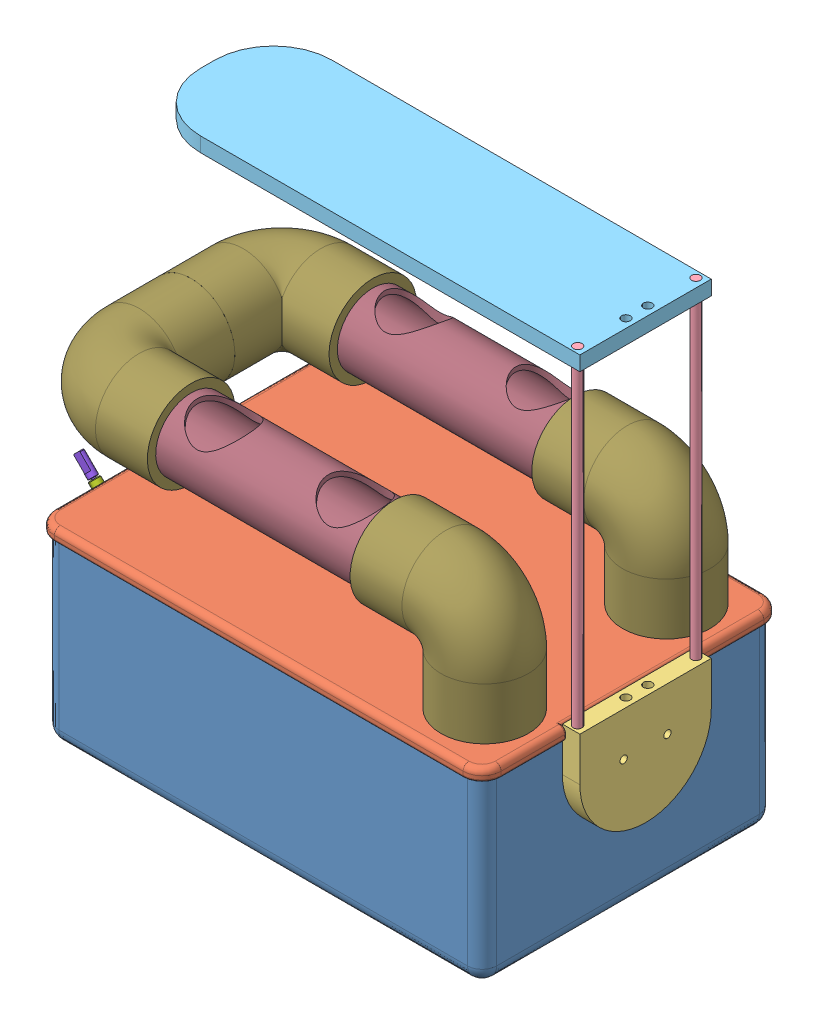
SolidWorks assembly Prototype1, configuration Default. Lengths in mm.
Overall size (357.64 356 206).
22 component instances, 13 part files, 37 mates.
Components (placement in the parent):
- Casing-1: Casing [Default] at (112.1733 69.847 255.1145) size (300 127 200)
- Tapa-1: Tapa [Default] at (112.1733 196.847 255.1145) size (306 8 206)
- BarsHolder-1: BarsHolder [Default] at (262.1733 170.847 255.1145) size (12 75 90)
- 15cmAluminumBar-1: 15cmAluminumBar [Default] at (268.1733 175.847 295.6145) size (6 250 6)
- 15cmAluminumBar-6: 15cmAluminumBar [Default] at (268.1733 175.847 214.6145) x (0.8 0 -0.6) z (0.6 0 0.8) size (6 250 6)
- LEDCasing-1: LEDCasing [Default] at (124.1733 425.847 255.1145) x (-1 0 0) z (0 -1 0) size (300 90 10)
- HMI_Assembly-1: HMI_Assembly [Default] at (61.0695 74.078 208.3108) x (0 0 1) z (-1 0 0) size (130 66.01 46.34)
  - HMI-1: HMI [Default] at (46.8038 55.769 108.8963) size (130 60 36.41)
  - KY-040 Rotary Encoder-1: KY-040 Rotary Encoder [Default] at (72.2658 91.6158 120.3711) x (0 0.707107 -0.707107) z (1 0 0) size (18.7 30.1 31.47)
    - Rotary Encoder-1: Rotary Encoder [Default] at (5.1929 2.265 12.688) size (11.8 14.9 15)
    - D-handle-1: D-handle [Default] at (5.1929 8.865 12.688) x (-0.994918 0 0.100689) z (-0.100689 0 -0.994918) size (6 20.2 6)
    - pcb-1: pcb [Default] at (-5.1071 1.765 2.138) x (0 0 1) z (-1 0 0) size (26.2 1.02 18.7)
    - 2.54 5PIN 90-1: 2.54 5PIN 90 [Default] at (-0.1071 2.265 26.008) x (-1 0 0) z (0 0 -1) size (12.7 7.32 8.85)
  - STEP 1602 Serial LCD Module.step-1: STEP 1602 Serial LCD Module.step [Default] at (27.4538 96.3236 118.4422) x (1 0 0) z (0 -0.707107 0.707107) size (80.2 17.64 36)
- Assem1-1: Assem1 [Default] at (270.3073 -107.7676 643.9382) x (-1 0 0) z (0 0 -1) size (327.44 96.36 184.4)
  - 1.5in Elbow-1: 1.5in Elbow [1.5in Elbow] at (44.134 370.8447 451.0537) x (-1 0 0) z (0 0 1) size (92.2 92.2 59.94)
  - 1.5in pipe-1: 1.5in pipe [30cm] at (280.804 370.8447 451.0537) x (0 -0.182542 0.983198) z (-1 0 0) size (48.56 48.56 210)
  - 1.5in Elbow-2: 1.5in Elbow [1.5in Elbow] at (307.474 370.8447 451.0537) x (1 0 0) z (0 1 0) size (92.2 92.2 59.94)
  - 1.5in pipe-2: 1.5in pipe [71.12cm] at (307.474 370.8447 424.3837) x (0.625868 0.779929 0) z (0 0 -1) size (48.56 48.56 71.12)
  - 1.5in Elbow-3: 1.5in Elbow [1.5in Elbow] at (307.474 370.8447 326.5937) x (1 0 0) z (0 -1 0) size (92.2 92.2 59.94)
  - 1.5in pipe-3: 1.5in pipe [30cm] at (280.804 370.8447 326.5937) x (0 0.100903 0.994896) z (-1 0 0) size (48.56 48.56 210)
  - 1.5in Elbow-4: 1.5in Elbow [1.5in Elbow] at (44.134 370.8447 326.5937) x (-1 0 0) z (0 0 1) size (92.2 92.2 59.94)
Mates (geometry in assembly coordinates):
- Coincident1: coincident anti-aligned: plane of Casing-1 through (112.1733 196.847 255.1145) normal (0 1 0); plane of Tapa-1 through (252.1733 196.847 345.1145) normal (0 -1 0)
- Coincident5: coincident anti-aligned: plane of Casing-1 through (262.1733 196.847 355.1145) normal (1 0 0); plane of BarsHolder-1 through (262.1733 170.847 255.1145) normal (-1 0 0)
- Coincident6: coincident aligned: plane of Tapa-1 through (252.1733 200.847 345.1145) normal (0 1 0); plane of BarsHolder-1 through (274.1733 200.847 300.1145) normal (0 1 0)
- Width1: width anti-aligned: plane of Casing-1 through (262.1733 196.847 355.1145) normal (0 0 1); plane of BarsHolder-1 through (262.1733 196.847 155.1145) normal (0 0 -1); plane of Casing-1 through (274.1733 170.847 210.1145) normal (0 0 -1); plane of BarsHolder-1 through (274.1733 170.847 300.1145) normal (0 0 1)
- Coincident7: coincident anti-aligned: plane of BarsHolder-1 through (268.1733 175.847 295.6145) normal (0 1 0); plane of 15cmAluminumBar-1 through (268.1733 175.847 295.6145) normal (0 -1 0)
- Concentric2: concentric anti-aligned: cylinder of BarsHolder-1 through (268.1733 175.847 295.6145) axis (0 1 0) radius 3; cylinder of 15cmAluminumBar-1 through (268.1733 425.847 295.6145) axis (0 -1 0) radius 3
- Coincident8: coincident anti-aligned: plane of BarsHolder-1 through (268.1733 175.847 262.6145) normal (0 1 0); plane of 15cmAluminumBar-2 through (268.1733 148.847 262.6145) normal (0 -1 0)
- Concentric3: concentric anti-aligned: cylinder of BarsHolder-1 through (268.1733 175.847 262.6145) axis (0 1 0) radius 3; cylinder of 15cmAluminumBar-2 through (268.1733 398.847 262.6145) axis (0 -1 0) radius 3
- Coincident9: coincident anti-aligned: circle of BarsHolder-1; plane of 15cmAluminumBar-4 through (268.1733 148.847 247.6145) normal (0 -1 0)
- Concentric4: concentric anti-aligned: cylinder of BarsHolder-1 through (268.1733 175.847 247.6145) axis (0 1 0) radius 3; cylinder of 15cmAluminumBar-4 through (268.1733 398.847 247.6145) axis (0 -1 0) radius 3
- Coincident10: coincident anti-aligned: plane of BarsHolder-1 through (268.1733 175.847 214.6145) normal (0 1 0); plane of 15cmAluminumBar-6 through (268.1733 175.847 214.6145) normal (0 -1 0)
- Concentric5: concentric anti-aligned: cylinder of BarsHolder-1 through (268.1733 175.847 214.6145) axis (0 1 0) radius 3; cylinder of 15cmAluminumBar-6 through (268.1733 425.847 214.6145) axis (0 -1 0) radius 3
- Coincident12: coincident aligned: plane of 15cmAluminumBar-1 through (268.1733 425.847 295.6145) normal (0 1 0); plane of LEDCasing-1 through (124.1733 425.847 255.1145) normal (0 1 0)
- Concentric7: concentric anti-aligned: cylinder of 15cmAluminumBar-6 through (268.1733 425.847 214.6145) axis (0 -1 0) radius 3; cylinder of LEDCasing-1 through (268.1733 415.847 214.6145) axis (0 1 0) radius 3
- Concentric8: concentric anti-aligned: cylinder of 15cmAluminumBar-1 through (268.1733 425.847 295.6145) axis (0 -1 0) radius 3; cylinder of LEDCasing-1 through (268.1733 415.847 295.6145) axis (0 1 0) radius 3
- Concentric9: concentric aligned: cone of NETCUP-1 through (180.3245 291.0607 257.7955) axis (0 -1 0); cylinder of PVC_TUBE_(100mm DIA X 300mm)-1 through (180.3245 353.5607 257.7955) axis (0 -1 0) radius 27.5
- Tangent1: tangent anti-aligned: plane of NETCUP-1 through (180.3245 291.0607 287.7955) normal (0 -1 0); cylinder of PVC_TUBE_(100mm DIA X 300mm)-1 through (-44.6755 253.5607 257.7955) axis (1 0 0) radius 37.5
- Concentric10: concentric aligned: cylinder of PVC_TUBE_(100mm DIA X 300mm)-1 through (30.3245 353.5607 257.7955) axis (0 -1 0) radius 27.5; cone of NETCUP-2 through (30.3245 291.0607 257.7955) axis (0 -1 0)
- Tangent2: tangent anti-aligned: cylinder of PVC_TUBE_(100mm DIA X 300mm)-1 through (-44.6755 253.5607 257.7955) axis (1 0 0) radius 37.5; plane of NETCUP-2 through (35.9781 291.0607 287.2579) normal (0 -1 0)
- Concentric11: concentric aligned: cylinder of PVC_END_CAP-1 through (-64.6755 253.5607 257.7955) axis (1 0 0) radius 39.5; cylinder of PVC_TUBE_(100mm DIA X 300mm)-1 through (-44.6755 253.5607 257.7955) axis (1 0 0) radius 37.5
- Distance1: distance = 20 mm anti-aligned: plane of PVC_END_CAP-1 through (-64.6755 253.5607 257.7955) normal (1 0 0); plane of PVC_TUBE_(100mm DIA X 300mm)-1 through (-44.6755 253.5607 257.7955) normal (-1 0 0)
- Concentric12: concentric anti-aligned: cylinder of PVC_TUBE_(100mm DIA X 300mm)-1 through (-44.6755 253.5607 257.7955) axis (1 0 0) radius 37.5; cylinder of PVC_END_CAP-2 through (275.3245 253.5607 257.7955) axis (-1 0 0) radius 39.5
- Distance2: distance = 20 mm anti-aligned: plane of PVC_END_CAP-2 through (275.3245 253.5607 257.7955) normal (-1 0 0); plane of PVC_TUBE_(100mm DIA X 300mm)-1 through (255.3245 253.5607 257.7955) normal (1 0 0)
- Coincident13: coincident anti-aligned: plane of Tapa-1 through (252.1733 200.847 345.1145) normal (0 1 0); plane of Casing2-1 through (112.1733 173.847 255.1145) normal (0 -1 0)
- Coincident14: coincident aligned: plane of Casing-1 through (262.1733 196.847 155.1145) normal (0 0 -1); plane of Casing2-1 through (262.1733 223.847 155.1145) normal (0 0 -1)
- Coincident15: coincident aligned: plane of Casing-1 through (-37.8267 196.847 355.1145) normal (-1 0 0); plane of Casing2-1 through (-37.8267 223.847 355.1145) normal (-1 0 0)
- Coincident16: coincident anti-aligned: plane of Casing2-1 through (112.1733 223.847 255.1145) normal (0 1 0); plane of Tapa2-1 through (252.1733 223.847 345.1145) normal (0 -1 0)
- Coincident17: coincident aligned: plane of Casing2-1 through (262.1733 223.847 155.1145) normal (0 0 -1); plane of Tapa2-1 through (252.1733 227.847 155.1145) normal (0 0 -1)
- Coincident18: coincident aligned: plane of Casing2-1 through (-37.8267 223.847 355.1145) normal (-1 0 0); plane of Tapa2-1 through (-37.8267 227.847 345.1145) normal (-1 0 0)
- Coincident19: coincident anti-aligned: plane of Casing-1 through (-37.8267 196.847 355.1145) normal (-1 0 0); plane of HMI_Assembly-1/HMI-1 through (-37.8267 189.847 320.1145) normal (1 0 0)
- Width2: width anti-aligned: plane of Casing-1 through (262.1733 196.847 155.1145) normal (0 0 -1); plane of HMI_Assembly-1/HMI-1 through (262.1733 196.847 355.1145) normal (0 0 1); plane of Casing-1 through (-47.8267 129.847 320.1145) normal (0 0 1); plane of HMI_Assembly-1/HMI-1 through (-47.8267 129.847 190.1145) normal (0 0 -1)
- Coincident21: coincident anti-aligned: plane of Casing-1 through (262.1733 196.847 355.1145) normal (0 0 1); plane of Tapa-1 through (-27.8267 192.847 355.1145) normal (0 0 -1)
- Coincident23: coincident anti-aligned: plane of Casing-1 through (262.1733 196.847 355.1145) normal (1 0 0); plane of Tapa-1 through (262.1733 192.847 345.1145) normal (-1 0 0)
- Distance3: distance = 60 mm aligned: plane of HMI_Assembly-1/HMI-1 through (-47.8267 129.847 320.1145) normal (0 -1 0); plane of Casing-1 through (112.1733 69.847 255.1145) normal (0 -1 0)
- Concentric13: concentric aligned: cylinder of Tapa-1 through (226.1733 182.847 317.3445) axis (0 1 0) radius 24.28; cone of Assem1-1/1.5in Elbow-4 through (226.1733 200.847 317.3445) axis (0 1 0)
- Concentric14: concentric aligned: cylinder of Tapa-1 through (226.1733 182.847 192.8845) axis (0 1 0) radius 24.28; cone of Assem1-1/1.5in Elbow-1 through (226.1733 200.847 192.8845) axis (0 1 0)
- Coincident25: coincident anti-aligned: plane of Tapa-1 through (252.1733 200.847 345.1145) normal (0 1 0); plane of Assem1-1/1.5in Elbow-1 through (256.1453 200.847 192.8845) normal (0 -1 0)
